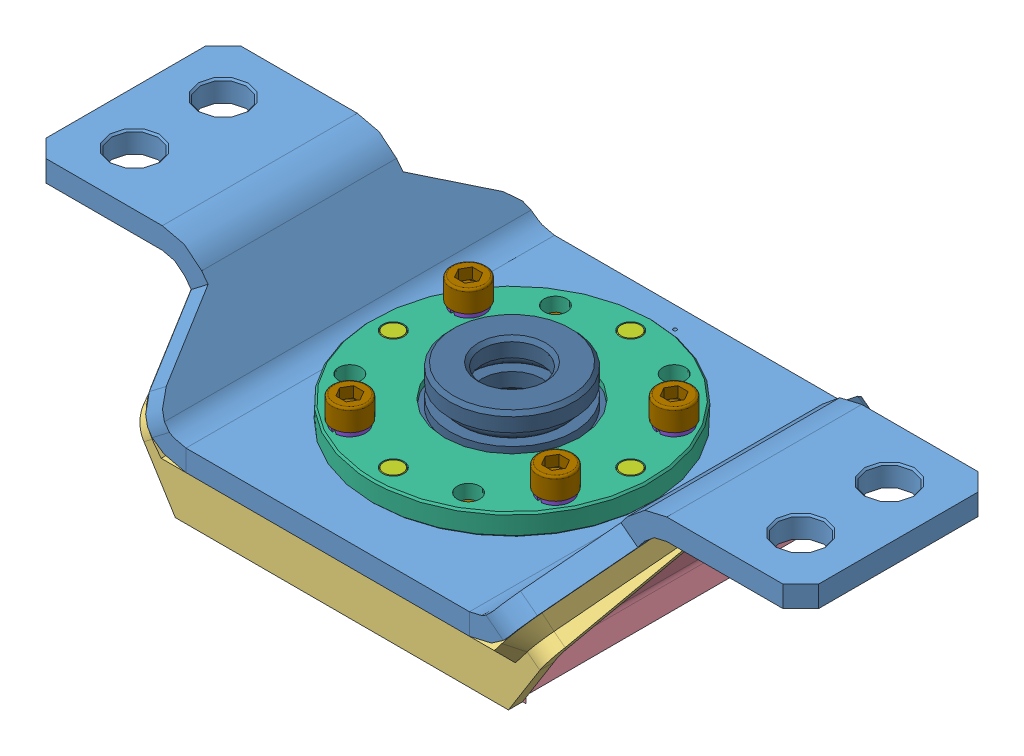
SolidWorks assembly Кронштейн 2х тензодатчиков в сборе в2, configuration По умолчанию. Lengths in mm.
Overall size (218 125.16 158.79).
31 component instances, 12 part files, 55 mates.
Components (placement in the parent):
- Кронштейн 2х тензодатчиков сварка в1-1: Кронштейн 2х тензодатчиков сварка в1 [По умолчанию] at origin size (218 125.16 158.79)
  - Кронштейн 2х тензодатчиков в3-1: Кронштейн 2х тензодатчиков в3 [По умолчанию] at origin size (218 32.5 104.87)
  - Ребро лев кронштейна 2х тензодатчиков в2-1: Ребро лев кронштейна 2х тензодатчиков в2 [с телами сварочных швов] at (0 -6 -44) size (135.34 40.9 37.66)
  - Ребро прав кронштейна 2х тензодатчиков в2-1: Ребро прав кронштейна 2х тензодатчиков в2 [с телами сварочных швов] at (10.7647 8.0289 75.6979) x (0.836641 -0.212893 -0.504686) z (0.504686 0.65772 0.559193) size (116.57 71.27 74.27)
  - Ребро прижимное кронштейна 2х тензодатчиков-1: Ребро прижимное кронштейна 2х тензодатчиков [Со сварочными швами] at (-41.9164 -22.5 0) x (-1 0 0) z (0 0 -1) size (21.61 33.01 88)
  - Ребро прижимное кронштейна 2х тензодатчиков-2: Ребро прижимное кронштейна 2х тензодатчиков [Со сварочными швами] at (41.9164 -22.5 0) size (21.61 33.01 88)
- Стакан нижнего радиального подшипника-1: Стакан нижнего радиального подшипника [По умолчанию] at (0 -6 0) x (-1 0 0) z (0 0 1) size (79 20 79)
- Стакан упорного подшипника-1: Стакан упорного подшипника [По умолчанию] at (0 6 0) size (79 6 79)
- Stift 3128n_gost-1: Stift 3128n_gost [Штифт 2.6X18 ГОСТ 3128-70] at (0 -12 33.5) size (6 18 6)
- Stift 3128n_gost-2: Stift 3128n_gost [Штифт 2.6X18 ГОСТ 3128-70] at (-33.5 -12 0) size (6 18 6)
- Stift 3128n_gost-3: Stift 3128n_gost [Штифт 2.6X18 ГОСТ 3128-70] at (0 -12 -33.5) size (6 18 6)
- Stift 3128n_gost-4: Stift 3128n_gost [Штифт 2.6X18 ГОСТ 3128-70] at (33.5 -12 0) size (6 18 6)
- Washer 6402_3_gost-1: Washer 6402_3_gost [Шайба 6 65Г 019 ГОСТ 6402-70] at (-16.75 6 29.0119) size (8.9 1.4 8.9)
- Washer 6402_3_gost-2: Washer 6402_3_gost [Шайба 6 65Г 019 ГОСТ 6402-70] at (-29.0119 6 -16.75) size (8.9 1.4 8.9)
- Washer 6402_3_gost-3: Washer 6402_3_gost [Шайба 6 65Г 019 ГОСТ 6402-70] at (29.0119 6 -16.75) size (8.9 1.4 8.9)
- Washer 6402_3_gost-4: Washer 6402_3_gost [Шайба 6 65Г 019 ГОСТ 6402-70] at (29.0119 6 16.75) size (8.9 1.4 8.9)
- Washer 6402_3_gost-5: Washer 6402_3_gost [Шайба 6 65Г 019 ГОСТ 6402-70] at (16.75 -12 29.0119) x (0.837169 0 0.546944) z (0.546944 0 -0.837169) size (8.9 1.4 8.9)
- Washer 6402_3_gost-6: Washer 6402_3_gost [Шайба 6 65Г 019 ГОСТ 6402-70] at (-29.0119 -12 16.75) x (0.837169 0 0.546944) z (0.546944 0 -0.837169) size (8.9 1.4 8.9)
- Washer 6402_3_gost-7: Washer 6402_3_gost [Шайба 6 65Г 019 ГОСТ 6402-70] at (16.75 -12 -29.0119) x (0.837169 0 0.546944) z (0.546944 0 -0.837169) size (8.9 1.4 8.9)
- Washer 6402_3_gost-8: Washer 6402_3_gost [Шайба 6 65Г 019 ГОСТ 6402-70] at (-16.75 -12 -29.0119) x (0.837169 0 0.546944) z (0.546944 0 -0.837169) size (8.9 1.4 8.9)
- socket head cap screw_din-1: socket head cap screw_din [DIN 912 M6 x 16 --- 16S] at (29.0119 13.4 -16.75) x (0 -1 0) z (0 0 1) size (22 10 10)
- socket head cap screw_din-2: socket head cap screw_din [DIN 912 M6 x 16 --- 16S] at (29.0119 13.4 16.75) x (0 -1 0) z (0 0 1) size (22 10 10)
- socket head cap screw_din-3: socket head cap screw_din [DIN 912 M6 x 16 --- 16S] at (-16.75 13.4 29.0119) x (0 -1 0) z (0 0 1) size (22 10 10)
- socket head cap screw_din-4: socket head cap screw_din [DIN 912 M6 x 16 --- 16S] at (-29.0119 13.4 -16.75) x (0 -1 0) z (0 0 1) size (22 10 10)
- socket head cap screw_din-5: socket head cap screw_din [DIN 912 M6 x 16 --- 16S] at (16.75 -19.4 -29.0119) x (0 1 0) z (0 0 1) size (22 10 10)
- socket head cap screw_din-6: socket head cap screw_din [DIN 912 M6 x 16 --- 16S] at (-16.75 -19.4 -29.0119) x (0 1 0) z (0 0 1) size (22 10 10)
- socket head cap screw_din-7: socket head cap screw_din [DIN 912 M6 x 16 --- 16S] at (-29.0119 -19.4 16.75) x (0 1 0) z (0 0 1) size (22 10 10)
- socket head cap screw_din-8: socket head cap screw_din [DIN 912 M6 x 16 --- 16S] at (16.75 -19.4 29.0119) x (0 1 0) z (0 0 1) size (22 10 10)
- Bear gost 7872_2-18203 ГОСТ 7872-89-1: Bear gost 7872_2-18203 ГОСТ 7872-89 [По умолчанию] at (-0.0133 0 0) x (0 1 0) z (0 0 1) size (15 38 38)
- Bear gost 9592-971801 ГОСТ 9592-75-1: Bear gost 9592-971801 ГОСТ 9592-75 [По умолчанию] at (0 -3 0) x (0 -1 0) z (0 0 1) size (19 42 42)
- Гайка фиксирующая-1: Гайка фиксирующая [По умолчанию] at (0 -19 0) x (-1 0 0) z (0 0 1) size (45 6.79 45)
Mates (geometry in assembly coordinates):
- Совпадение1: coincident anti-aligned: plane of Стакан нижнего радиального подшипника-1 through (25.9763 -6 0) normal (0 1 0); plane of Кронштейн 2х тензодатчиков сварка в1-1/Кронштейн 2х тензодатчиков в3-1 through (109 -6 52) normal (0 -1 0)
- Концентрический1: concentric aligned: cylinder of Кронштейн 2х тензодатчиков сварка в1-1/Кронштейн 2х тензодатчиков в3-1 through (0 -6 0) axis (0 1 0) radius 12.5; cylinder of Стакан нижнего радиального подшипника-1 through (0 -6 0) axis (0 1 0) radius 21
- Концентрический2: concentric anti-aligned: cylinder of Кронштейн 2х тензодатчиков сварка в1-1/Кронштейн 2х тензодатчиков в3-1 through (0 -6 33.5) axis (0 1 0) radius 3; cylinder of Стакан нижнего радиального подшипника-1 through (0 -6 33.5) axis (0 -1 0) radius 3
- Совпадение2: coincident anti-aligned: plane of Кронштейн 2х тензодатчиков сварка в1-1/Кронштейн 2х тензодатчиков в3-1 through (109 0 52) normal (0 1 0); plane of Стакан упорного подшипника-1 through (0 0 0) normal (0 -1 0)
- Концентрический3: concentric aligned: cylinder of Кронштейн 2х тензодатчиков сварка в1-1/Кронштейн 2х тензодатчиков в3-1 through (0 -6 0) axis (0 1 0) radius 12.5; cylinder of Стакан упорного подшипника-1 through (0 0 0) axis (0 1 0) radius 19
- Концентрический4: concentric aligned: cylinder of Кронштейн 2х тензодатчиков сварка в1-1/Кронштейн 2х тензодатчиков в3-1 through (0 -6 -33.5) axis (0 1 0) radius 3; cylinder of Стакан упорного подшипника-1 through (0 0 -33.5) axis (0 1 0) radius 3
- Концентрический5: concentric aligned: cylinder of Стакан упорного подшипника-1 through (-16.75 6 29.0119) axis (0 1 0) radius 3.2; cylinder of Washer 6402_3_gost-1 through (-16.75 21.7597 29.0119) axis (0 1 0) radius 3.05
- Совпадение3: coincident anti-aligned: plane of Стакан упорного подшипника-1 through (0 6 0) normal (0 1 0); plane of Washer 6402_3_gost-1 through (-19.8 6 29.0119) normal (0 -1 0)
- Концентрический6: concentric aligned: cylinder of Washer 6402_3_gost-2 through (-29.0119 21.7597 -16.75) axis (0 1 0) radius 3.05; cylinder of Стакан упорного подшипника-1 through (-29.0119 6 -16.75) axis (0 1 0) radius 3.2
- Совпадение4: coincident anti-aligned: plane of Стакан упорного подшипника-1 through (0 6 0) normal (0 1 0); plane of Washer 6402_3_gost-2 through (-32.0619 6 -16.75) normal (0 -1 0)
- Концентрический7: concentric aligned: cylinder of Washer 6402_3_gost-3 through (29.0119 21.7597 -16.75) axis (0 1 0) radius 3.05; cylinder of Стакан упорного подшипника-1 through (29.0119 6 -16.75) axis (0 1 0) radius 3.2
- Совпадение5: coincident anti-aligned: plane of Стакан упорного подшипника-1 through (0 6 0) normal (0 1 0); plane of Washer 6402_3_gost-3 through (25.9619 6 -16.75) normal (0 -1 0)
- Концентрический8: concentric aligned: cylinder of Стакан упорного подшипника-1 through (29.0119 6 16.75) axis (0 1 0) radius 3.2; cylinder of Washer 6402_3_gost-4 through (29.0119 21.7597 16.75) axis (0 1 0) radius 3.05
- Совпадение6: coincident anti-aligned: plane of Стакан упорного подшипника-1 through (0 6 0) normal (0 1 0); plane of Washer 6402_3_gost-4 through (25.9619 6 16.75) normal (0 -1 0)
- Концентрический9: concentric aligned: cylinder of Стакан нижнего радиального подшипника-1 through (16.75 -12 29.0119) axis (0 -1 0) radius 3.2; cylinder of Washer 6402_3_gost-5 through (16.75 -27.7597 29.0119) axis (0 -1 0) radius 3.05
- Совпадение7: coincident anti-aligned: plane of Стакан нижнего радиального подшипника-1 through (25.9763 -12 0) normal (0 -1 0); plane of Washer 6402_3_gost-5 through (14.1966 -12 27.3437) normal (0 1 0)
- Концентрический10: concentric aligned: cylinder of Стакан нижнего радиального подшипника-1 through (-29.0119 -12 16.75) axis (0 -1 0) radius 3.2; cylinder of Washer 6402_3_gost-6 through (-29.0119 -27.7597 16.75) axis (0 -1 0) radius 3.05
- Совпадение8: coincident anti-aligned: plane of Стакан нижнего радиального подшипника-1 through (25.9763 -12 0) normal (0 -1 0); plane of Washer 6402_3_gost-6 through (-31.5652 -12 15.0818) normal (0 1 0)
- Концентрический11: concentric aligned: cylinder of Washer 6402_3_gost-7 through (16.75 -27.7597 -29.0119) axis (0 -1 0) radius 3.05; cylinder of Стакан нижнего радиального подшипника-1 through (16.75 -12 -29.0119) axis (0 -1 0) radius 3.2
- Совпадение9: coincident anti-aligned: plane of Стакан нижнего радиального подшипника-1 through (25.9763 -12 0) normal (0 -1 0); plane of Washer 6402_3_gost-7 through (14.1966 -12 -30.68) normal (0 1 0)
- Концентрический12: concentric aligned: cylinder of Washer 6402_3_gost-8 through (-16.75 -27.7597 -29.0119) axis (0 -1 0) radius 3.05; cylinder of Стакан нижнего радиального подшипника-1 through (-16.75 -12 -29.0119) axis (0 -1 0) radius 3.2
- Совпадение10: coincident anti-aligned: plane of Стакан нижнего радиального подшипника-1 through (25.9763 -12 0) normal (0 -1 0); plane of Washer 6402_3_gost-8 through (-19.3034 -12 -30.68) normal (0 1 0)
- Концентрический14: concentric aligned: cylinder of socket head cap screw_din-1 through (29.0119 45.15 -16.75) axis (0 1 0) radius 5; cylinder of Стакан упорного подшипника-1 through (29.0119 6 -16.75) axis (0 1 0) radius 3.2
- Совпадение12: coincident anti-aligned: plane of Washer 6402_3_gost-3 through (25.9619 7.4 -16.75) normal (0 1 0); plane of socket head cap screw_din-1 through (34.0119 7.4 -16.75) normal (0 -1 0)
- Концентрический15: concentric aligned: cylinder of Стакан упорного подшипника-1 through (29.0119 6 16.75) axis (0 1 0) radius 3.2; cylinder of socket head cap screw_din-2 through (29.0119 45.15 16.75) axis (0 1 0) radius 5
- Совпадение13: coincident anti-aligned: plane of Washer 6402_3_gost-4 through (25.9619 7.4 16.75) normal (0 1 0); plane of socket head cap screw_din-2 through (34.0119 7.4 16.75) normal (0 -1 0)
- Концентрический16: concentric aligned: cylinder of Стакан упорного подшипника-1 through (-16.75 6 29.0119) axis (0 1 0) radius 3.2; cylinder of socket head cap screw_din-3 through (-16.75 45.15 29.0119) axis (0 1 0) radius 5
- Совпадение14: coincident anti-aligned: plane of Washer 6402_3_gost-1 through (-19.8 7.4 29.0119) normal (0 1 0); plane of socket head cap screw_din-3 through (-11.75 7.4 29.0119) normal (0 -1 0)
- Концентрический17: concentric aligned: cylinder of socket head cap screw_din-4 through (-29.0119 45.15 -16.75) axis (0 1 0) radius 5; cylinder of Стакан упорного подшипника-1 through (-29.0119 6 -16.75) axis (0 1 0) radius 3.2
- Совпадение15: coincident anti-aligned: plane of Washer 6402_3_gost-2 through (-32.0619 7.4 -16.75) normal (0 1 0); plane of socket head cap screw_din-4 through (-24.0119 7.4 -16.75) normal (0 -1 0)
- Концентрический18: concentric aligned: cylinder of socket head cap screw_din-5 through (16.75 -51.15 -29.0119) axis (0 -1 0) radius 5; cylinder of Стакан нижнего радиального подшипника-1 through (16.75 -12 -29.0119) axis (0 -1 0) radius 3.2
- Совпадение16: coincident anti-aligned: plane of Washer 6402_3_gost-7 through (14.1966 -13.4 -30.68) normal (0 -1 0); plane of socket head cap screw_din-5 through (11.75 -13.4 -29.0119) normal (0 1 0)
- Концентрический19: concentric aligned: cylinder of Washer 6402_3_gost-8 through (-16.75 -27.7597 -29.0119) axis (0 -1 0) radius 4.45; cylinder of socket head cap screw_din-6 through (-16.75 -51.15 -29.0119) axis (0 -1 0) radius 5
- Совпадение17: coincident anti-aligned: plane of Washer 6402_3_gost-8 through (-19.3034 -13.4 -30.68) normal (0 -1 0); plane of socket head cap screw_din-6 through (-21.75 -13.4 -29.0119) normal (0 1 0)
- Концентрический201: concentric aligned: cylinder of Стакан нижнего радиального подшипника-1 through (-29.0119 -12 16.75) axis (0 -1 0) radius 3.2; cylinder of socket head cap screw_din-7 through (-29.0119 -51.15 16.75) axis (0 -1 0) radius 5
- Совпадение181: coincident anti-aligned: plane of Washer 6402_3_gost-6 through (-31.5652 -13.4 15.0818) normal (0 -1 0); plane of socket head cap screw_din-7 through (-34.0119 -13.4 16.75) normal (0 1 0)
- Концентрический21: concentric aligned: cylinder of Стакан нижнего радиального подшипника-1 through (16.75 -12 29.0119) axis (0 -1 0) radius 3.2; cylinder of socket head cap screw_din-8 through (16.75 -51.15 29.0119) axis (0 -1 0) radius 5
- Совпадение19: coincident anti-aligned: plane of Washer 6402_3_gost-5 through (14.1966 -13.4 27.3437) normal (0 -1 0); plane of socket head cap screw_din-8 through (11.75 -13.4 29.0119) normal (0 1 0)
- Концентрический22: concentric anti-aligned: cylinder of Стакан упорного подшипника-1 through (-33.5 0 0) axis (0 1 0) radius 3; cylinder of Stift 3128n_gost-2 through (-33.5 -12 0) axis (0 -1 0) radius 3
- Концентрический23: concentric anti-aligned: cylinder of Стакан упорного подшипника-1 through (0 0 -33.5) axis (0 1 0) radius 3; cylinder of Stift 3128n_gost-3 through (0 -12 -33.5) axis (0 -1 0) radius 3
- Концентрический24: concentric anti-aligned: cylinder of Стакан упорного подшипника-1 through (0 0 33.5) axis (0 1 0) radius 3; cylinder of Stift 3128n_gost-1 through (0 -12 33.5) axis (0 -1 0) radius 3
- Концентрический25: concentric anti-aligned: cylinder of Стакан упорного подшипника-1 through (33.5 0 0) axis (0 1 0) radius 3; cylinder of Stift 3128n_gost-4 through (33.5 -12 0) axis (0 -1 0) radius 3
- Совпадение20: coincident aligned: plane of Стакан упорного подшипника-1 through (0 6 0) normal (0 1 0); plane of Stift 3128n_gost-4 through (33.5 6 0) normal (0 1 0)
- Совпадение21: coincident aligned: plane of Стакан упорного подшипника-1 through (0 6 0) normal (0 1 0); plane of Stift 3128n_gost-1 through (0 6 33.5) normal (0 1 0)
- Совпадение22: coincident aligned: plane of Стакан упорного подшипника-1 through (0 6 0) normal (0 1 0); plane of Stift 3128n_gost-2 through (-33.5 6 0) normal (0 1 0)
- Совпадение23: coincident aligned: plane of Стакан упорного подшипника-1 through (0 6 0) normal (0 1 0); plane of Stift 3128n_gost-3 through (0 6 -33.5) normal (0 1 0)
- Совпадение24: coincident anti-aligned: plane of Кронштейн 2х тензодатчиков сварка в1-1/Кронштейн 2х тензодатчиков в3-1 through (109 0 52) normal (0 1 0); plane of Bear gost 7872_2-18203 ГОСТ 7872-89-1 through (-18 0 0) normal (0 -1 0)
- Концентрический26: concentric anti-aligned: cylinder of Стакан упорного подшипника-1 through (0 0 0) axis (0 1 0) radius 19; cylinder of Bear gost 7872_2-18203 ГОСТ 7872-89-1 through (0 1.8 0) axis (0 -1 0) radius 19
- Совпадение25: coincident anti-aligned: plane of Кронштейн 2х тензодатчиков сварка в1-1/Кронштейн 2х тензодатчиков в3-1 through (109 -6 52) normal (0 -1 0); plane of Bear gost 9592-971801 ГОСТ 9592-75-1 through (-5.4704 -6 0) normal (0 1 0)
- Концентрический27: concentric aligned: cylinder of Стакан нижнего радиального подшипника-1 through (0 -6 0) axis (0 1 0) radius 21; cylinder of Bear gost 9592-971801 ГОСТ 9592-75-1 through (0 -3 0) axis (0 1 0) radius 21
- Совпадение26: coincident anti-aligned: plane of Гайка фиксирующая-1 through (0 -19 0) normal (0 1 0); plane of Bear gost 9592-971801 ГОСТ 9592-75-1 through (-5.4704 -19 0) normal (0 -1 0)
- Концентрический28: concentric aligned: cylinder of Стакан нижнего радиального подшипника-1 through (0 -6 0) axis (0 1 0) radius 27; cylinder of Гайка фиксирующая-1 through (0 -25 0) axis (0 1 0) radius 15
- Параллельность1: parallel aligned: plane of Кронштейн 2х тензодатчиков сварка в1-1/Ребро прав кронштейна 2х тензодатчиков в2-1 through (0 -22.5 44) normal (0 0 -1); plane of Гайка фиксирующая-1 through (-4 -19 16.4568) normal (0 0 -1)
- Параллельность2: parallel aligned: plane of Кронштейн 2х тензодатчиков сварка в1-1/Ребро прав кронштейна 2х тензодатчиков в2-1 through (0 -22.5 48) normal (0 0 1); plane of Bear gost 7872_2-18203 ГОСТ 7872-89-1 through (-0.0133 0 0) normal (0 0 1)
- Параллельность3: parallel aligned: plane of Кронштейн 2х тензодатчиков сварка в1-1/Ребро прав кронштейна 2х тензодатчиков в2-1 through (0 -22.5 48) normal (0 0 1); plane of Bear gost 9592-971801 ГОСТ 9592-75-1 through (0 -3 0) normal (0 0 1)
